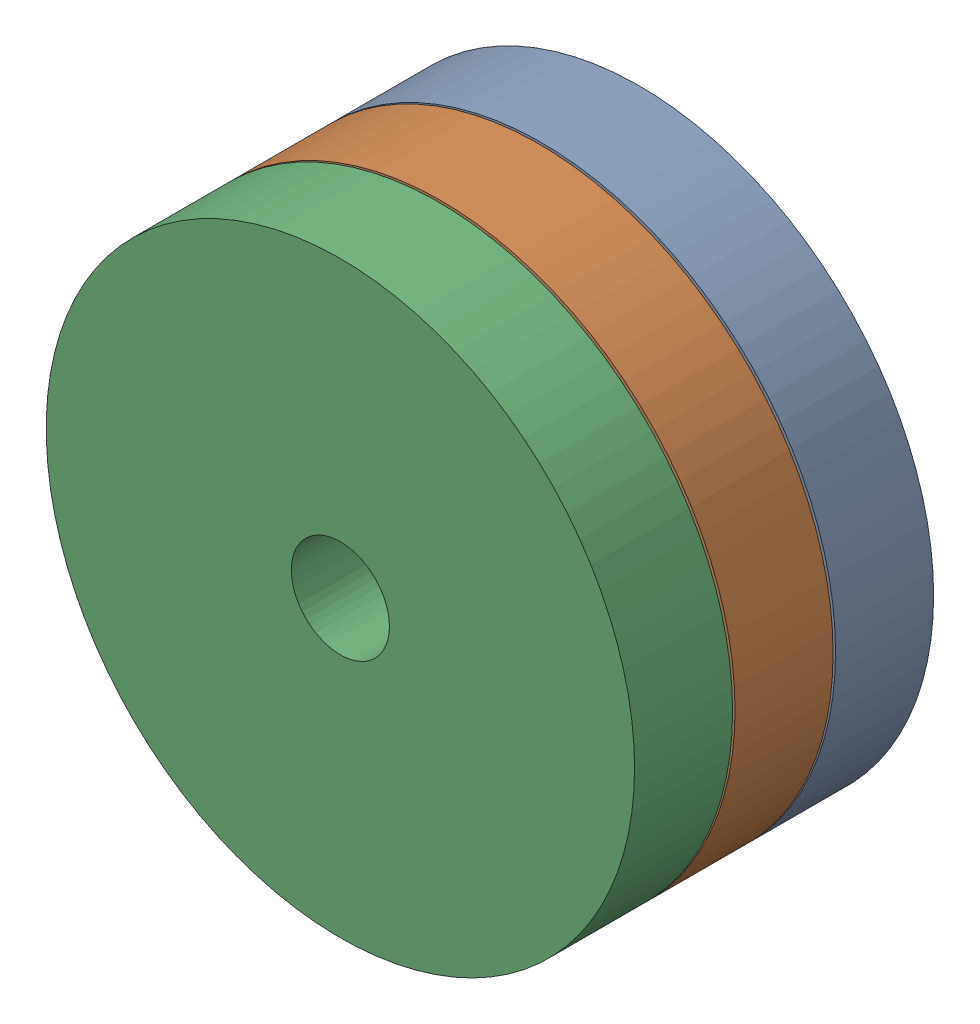
SolidWorks assembly Produit3, configuration Default. Lengths in mm.
Overall size (120 120 61).
3 component instances, 1 part files, 0 mates.
Components (placement in the parent):
- Part_Gateau2-1: Part_Gateau2 [Default] at origin size (120 120 20)
- Part_Gateau2-2: Part_Gateau2 [Default] at (0 0 20.5) size (120 120 20)
- Part_Gateau2-3: Part_Gateau2 [Default] at (0 0 41) size (120 120 20)
